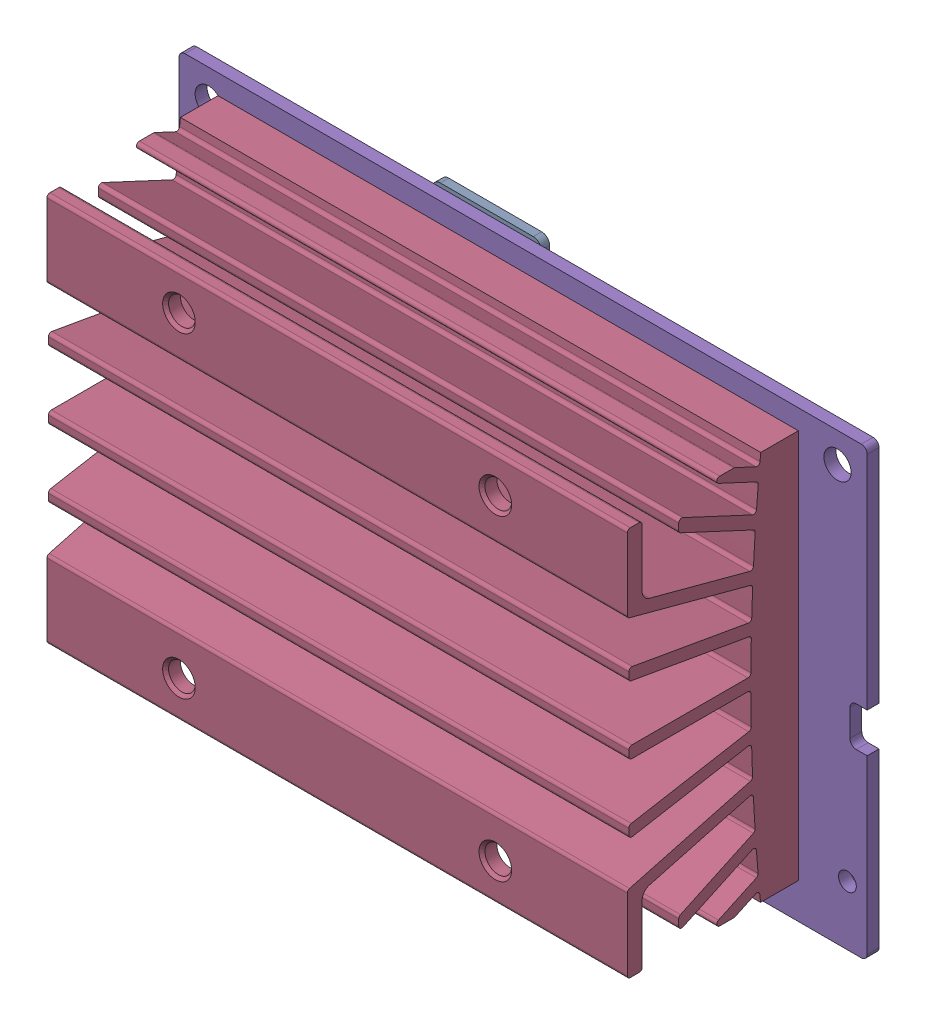
SolidWorks assembly 244-63448-0000-000_ASM, configuration 244-63448-0000-000_ASM. Lengths in mm.
Overall size (69.6 45 21.37).
13 component instances, 6 part files, 0 mates.
Components (placement in the parent):
- 142-13448-1000-A02_ASM-1: 142-13448-1000-A02_ASM [142-13448-1000-A02_ASM] at origin size (23 37.01 4.01)
  - 080-0051-000_3-1: 080-0051-000_3 [080-0051-000_3] at (28.331 29.139 0) x (-1 0 0) z (0 0 -1) size (13.4 17 1.28)
  - TM670M-A2_1-1: TM670M-A2_1 [TM670M-A2_1] at (23.7 13.45 1.2) size (23 23 1.29)
- 142-13448-1000-A02-SKU0000_ASM-1: 142-13448-1000-A02-SKU0000_ASM [142-13448-1000-A02-SKU0000_ASM] at origin size (23 23 1.29)
  - TM670M-A2_1-1: TM670M-A2_1 [TM670M-A2_1] at (23.7 13.45 1.2) size (23 23 1.29)
- PORG_HSK_ASSY_ASM-1: PORG_HSK_ASSY_ASM [PORG_HSK_ASSY_ASM] at (0 0 4.01) size (58.7 39.4 17.3)
  - PORG_HEAT_SINK-1: PORG_HEAT_SINK [PORG_HEAT_SINK] at origin size (58.7 39.4 17.3)
- 142-63448-1GEN_A00-1: 142-63448-1GEN_A00 [142-63448-1GEN_A00] at origin size (69.6 45 1.2)
- PORG_LEAF_SPRING_DRAWN-1: PORG_LEAF_SPRING_DRAWN [PORG_LEAF_SPRING_DRAWN] at (0 0 -0.4) x (1 0.000001 0) z (0 0 1) size (39.83 21.3 1.2)
- PORG_LEAF_SPRING_SCREW-1: PORG_LEAF_SPRING_SCREW [PORG_LEAF_SPRING_SCREW] at (6.9871 5.9982 5.21) x (0 0 -1) z (0 1 0) size (6.41 4.7 4.7)
- PORG_LEAF_SPRING_SCREW-2: PORG_LEAF_SPRING_SCREW [PORG_LEAF_SPRING_SCREW] at (6.9871 20.9018 5.21) x (0 0 -1) z (0 1 0) size (6.41 4.7 4.7)
- PORG_LEAF_SPRING_SCREW-3: PORG_LEAF_SPRING_SCREW [PORG_LEAF_SPRING_SCREW] at (40.4129 20.9018 5.21) x (0 0 -1) z (0 1 0) size (6.41 4.7 4.7)
- PORG_LEAF_SPRING_SCREW-4: PORG_LEAF_SPRING_SCREW [PORG_LEAF_SPRING_SCREW] at (40.4129 5.9982 5.21) x (0 0 -1) z (0 1 0) size (6.41 4.7 4.7)
